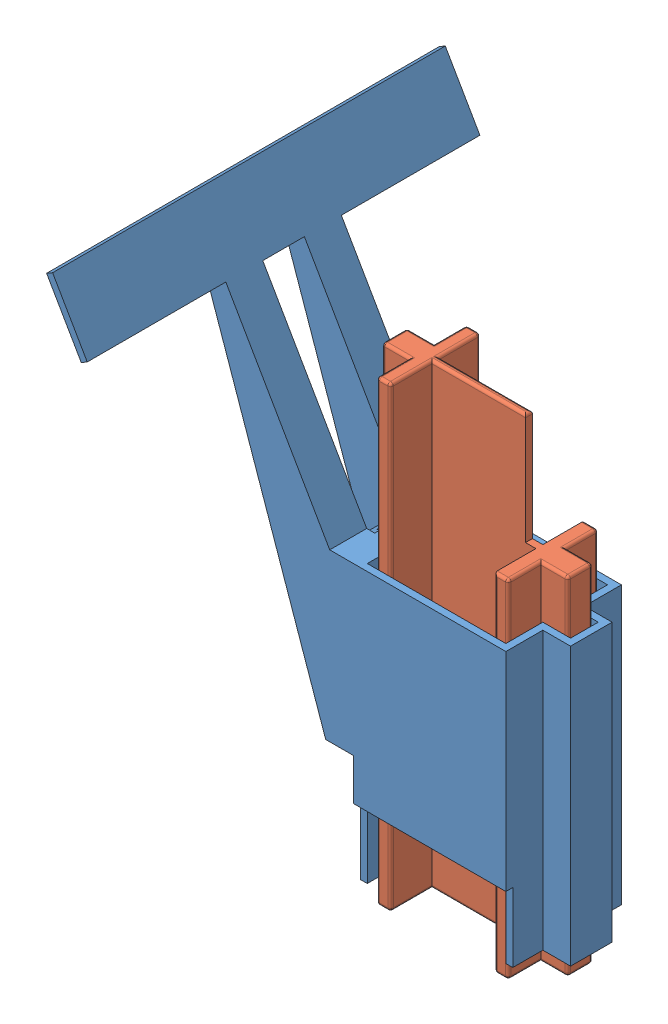
SolidWorks assembly Baugruppe1, configuration Standard. Lengths in mm.
Overall size (25.14 38.72 28.34).
2 component instances, 2 part files, 3 mates.
Components (placement in the parent):
- Mittelteil - 90 grad versetzt vergrößert für 4-1: Mittelteil - 90 grad versetzt vergrößert für 4 [Standard] at origin size (25.14 37.32 28.34)
- Schlitten 0-5 - vergrößert für 4-1: Schlitten 0-5 - vergrößert für 4 [Standard] at (0 23.5991 0) x (-1 0 0) z (0 -1 0) size (13.4 6.48 33)
Mates (geometry in assembly coordinates):
- Breite1: width anti-aligned: plane of Schlitten 0-5 - vergrößert für 4-1 through (3.75 31.5991 0.25) normal (0 0 1); plane of Mittelteil - 90 grad versetzt vergrößert für 4-1 through (-3.75 31.5991 -0.25) normal (0 0 -1); plane of Schlitten 0-5 - vergrößert für 4-1 through (5 20 3.67) normal (0 0 -1); plane of Mittelteil - 90 grad versetzt vergrößert für 4-1 through (5 20 -3.67) normal (0 0 1)
- Breite2: width aligned: plane of Schlitten 0-5 - vergrößert für 4-1 through (-6.7 -1.4009 0.9) normal (-1 0 0); plane of Mittelteil - 90 grad versetzt vergrößert für 4-1 through (6.7 -1.4009 0.9) normal (1 0 0); plane of Schlitten 0-5 - vergrößert für 4-1 through (-7 20 1) normal (1 0 0); plane of Mittelteil - 90 grad versetzt vergrößert für 4-1 through (7 20 1) normal (-1 0 0)
- Parallel1: parallel anti-aligned: plane of Mittelteil - 90 grad versetzt vergrößert für 4-1 through (0 20 0) normal (0 1 0); plane of Schlitten 0-5 - vergrößert für 4-1 through (0 -1.4009 0) normal (0 -1 0)
